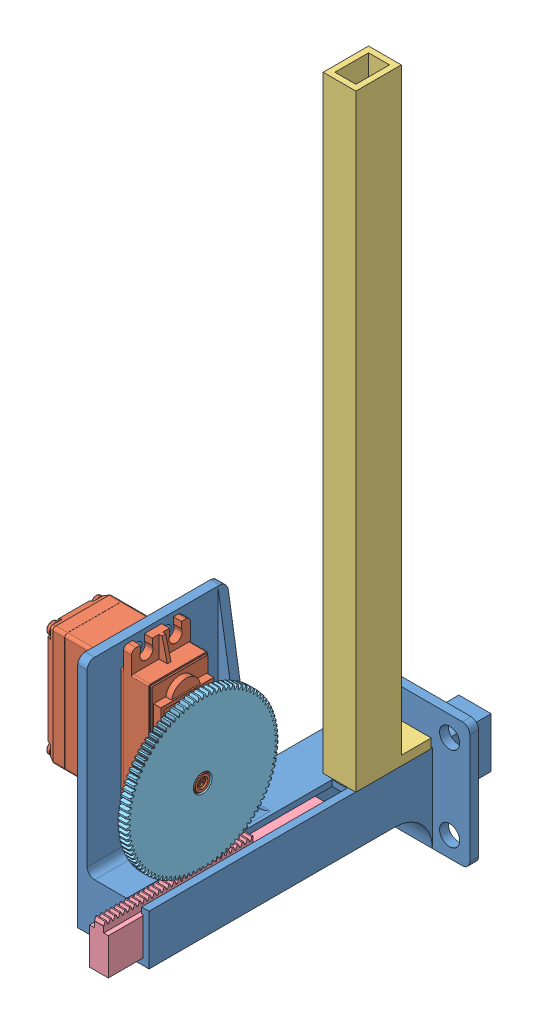
SolidWorks assembly FeederAssemV6, configuration Default. Lengths in mm.
Overall size (60.44 236.07 127.87).
5 component instances, 5 part files, 10 mates.
Components (placement in the parent):
- JawFeederV6-1: JawFeederV6 [Default] at (119.8417 67.1221 156.4958) size (36.94 92.64 116.3)
- FeederServo-1: FeederServo [Default] at (119.2979 116.7382 248.7118) x (0 1 0) z (1 0 0) size (54.3 20 43.9)
- FeederChimney-1: FeederChimney [Default] at (117.8417 85.2971 200.6118) size (11.11 206.38 25.59)
- FeederPlungerV2-1: FeederPlungerV2 [2662N54] at (123.4104 79.5681 231.5641) x (0 0 1) z (-1 0 0) size (76.2 15.62 6.35)
- DriveGear-1: DriveGear [2662N26] at (124.9979 106.8882 248.7118) x (0 -0.135158 0.990824) z (-1 0 0) size (51.87 51.87 9.56)
Mates (geometry in assembly coordinates):
- Coincident4: coincident anti-aligned: line of JawFeederV6-1 through (126.9537 82.1221 198.6118) axis (0 0 -1); line of FeederChimney-1 through (126.9537 82.1221 187.1818) axis (0 0 1)
- Coincident5: coincident anti-aligned: line of JawFeederV6-1 through (119.8417 82.1221 198.6118) axis (1 0 0); line of FeederChimney-1 through (126.9537 82.1221 198.6118) axis (-1 0 0)
- Distance4: distance = 0.381 mm anti-aligned: plane of FeederPlungerV2-1 through (120.2227 79.5681 206.1641) normal (-1 0 0); plane of JawFeederV6-1 through (119.8417 67.1221 232.6958) normal (1 0 0)
- Coincident16: coincident anti-aligned: plane of JawFeederV6-1 through (119.8417 67.1221 232.6958) normal (0 1 0); plane of FeederPlungerV2-1 through (120.2227 67.1221 206.1641) normal (0 -1 0)
- Concentric1: concentric anti-aligned: circle of FeederServo-1; cylinder of DriveGear-1 through (121.8229 106.8882 248.7118) axis (1 0 0) radius 3.175
- Coincident17: coincident aligned: plane of FeederServo-1 through (124.9979 106.8882 248.7118) normal (1 0 0); plane of DriveGear-1 through (124.9979 132.5585 252.2135) normal (1 0 0)
- Parallel1: parallel anti-aligned: plane of FeederServo-1 through (108.0979 136.1882 238.7118) normal (0 0 -1); plane of FeederChimney-1 through (117.8417 288.4971 200.6118) normal (0 0 1)
- Coincident19: coincident aligned: plane of FeederPlungerV2-1 through (124.9979 79.5681 282.3641) normal (1 0 0); plane of DriveGear-1 through (124.9979 132.5585 252.2135) normal (1 0 0)
- Coincident20: coincident: point of FeederPlungerV2-1; circle of DriveGear-1
- Distance5: distance = 38.1 mm anti-aligned: plane of FeederServo-1 through (108.0979 136.1882 238.7118) normal (0 0 -1); plane of FeederChimney-1 through (117.8417 288.4971 200.6118) normal (0 0 1)
